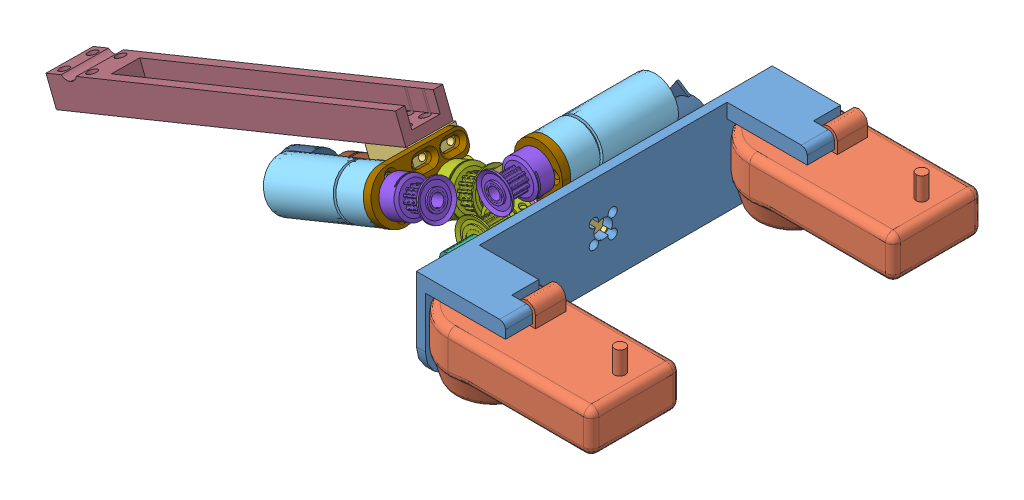
SolidWorks assembly VISION_HEAD_ASM, configuration Default. Lengths in mm.
Overall size (241.71 75.27 131.7).
29 component instances, 14 part files, 15 mates.
Components (placement in the parent):
- Head-Camera-Support-V2-1: Head-Camera-Support-V2 [Default] at origin size (30 32 119.8)
- LOGITECH_USB_CAM-1: LOGITECH_USB_CAM [Default] at (-11.43 -3.81 7.9) x (0 0 -1) z (0 -1 0) size (30.1 63.31 29.21)
- LOGITECH_USB_CAM-2: LOGITECH_USB_CAM [Default] at (-11.43 -3.81 -93.7) x (0 0 -1) z (0 -1 0) size (30.1 63.31 29.21)
- head-pin-joint-2: head-pin-joint [Default] at (-28 -14 -42.9) x (0 1 0) z (0 0 1) size (48.11 26.33 83.16)
  - n05-headyoke-1: n05-headyoke [Default] at origin size (15.88 21.91 15.88)
  - p1875bearing-57155K319-MCM-1: p1875bearing-57155K319-MCM [Default] at (0 13.97 5.5499) x (0 0 -1) z (0 -1 0) size (3.17 11.18 11.18)
  - p1875bearing-57155K319-MCM-2: p1875bearing-57155K319-MCM [Default] at (0 13.97 -5.5499) x (0 0 1) z (0 -1 0) size (3.17 11.18 11.18)
  - MAXON-AMAX16-110049-110323-1: MAXON-AMAX16-110049-110323 [Default] at (17.4625 8.128 -28.5125) x (0 0 -1) z (1 0 0) size (48.2 16 16)
  - n06-p1875shaft-1: n06-p1875shaft [Default] at (0 13.97 -15.0749) size (4.76 4.76 50.8)
  - a_6d16-016df2506-p1875bore-16teeth-1: a_6d16-016df2506-p1875bore-16teeth [Default] at (0 13.97 17.218) x (0.167713 -0.985836 0) z (0 0 -1) size (14.73 14.73 14.29)
  - a_6d16m012df6003-3mm-bored-to-4mm-1: a_6d16m012df6003-3mm-bored-to-4mm [Default] at (17.4625 8.128 17.2524) x (-0.948708 0.316155 0) z (0 0 -1) size (12.2 12.2 14.3)
  - a_6n16-015df1206-2: a_6n16-015df1206 [Default] at (-14.2838 6.954 15.9813) x (0.986257 0.164531 -0.015045) z (-0.021924 0.040076 -0.998956) size (14.1 14.1 11.13) (hidden)
  - n09-motor-holder-1: n09-motor-holder [Default] at (17.4625 8.128 7.9375) size (33.53 16.26 2.9)
  - POT-eti-sys-EUP125-1: POT-eti-sys-EUP125 [Default] at (0 13.97 -47.4345) x (0 0 -1) z (0.836462 -0.548026 0) size (30.58 15.39 13)
  - 000_helical-coupling-6208K53-MCM-1: 000_helical-coupling-6208K53-MCM [Default] at (0 13.97 -18.3769) size (12.7 12.7 19.05)
- head-pin-joint-3: head-pin-joint [Default] at (-90.0766 -18.4589 -43.0141) x (-0.003074 0.007569 0.999967) z (0.926512 0.376265 0) size (48.11 26.33 83.16)
  - n05-headyoke-1: n05-headyoke [Default] at origin size (15.88 21.91 15.88)
  - p1875bearing-57155K319-MCM-1: p1875bearing-57155K319-MCM [Default] at (0 13.97 5.5499) x (0 0 -1) z (0 -1 0) size (3.17 11.18 11.18)
  - p1875bearing-57155K319-MCM-2: p1875bearing-57155K319-MCM [Default] at (0 13.97 -5.5499) x (0 0 1) z (0 -1 0) size (3.17 11.18 11.18)
  - MAXON-AMAX16-110049-110323-1: MAXON-AMAX16-110049-110323 [Default] at (17.4625 8.128 -28.5125) x (0 0 -1) z (1 0 0) size (48.2 16 16)
  - n06-p1875shaft-1: n06-p1875shaft [Default] at (0 13.97 -15.0749) size (4.76 4.76 50.8)
  - a_6d16-016df2506-p1875bore-16teeth-1: a_6d16-016df2506-p1875bore-16teeth [Default] at (0 13.97 17.218) x (0.167713 -0.985836 0) z (0 0 -1) size (14.73 14.73 14.29)
  - a_6d16m012df6003-3mm-bored-to-4mm-1: a_6d16m012df6003-3mm-bored-to-4mm [Default] at (17.4625 8.128 17.2524) x (-0.948708 0.316155 0) z (0 0 -1) size (12.2 12.2 14.3)
  - a_6n16-015df1206-2: a_6n16-015df1206 [Default] at (-14.2838 6.954 15.9813) x (0.986257 0.164531 -0.015045) z (-0.021924 0.040076 -0.998956) size (14.1 14.1 11.13) (hidden)
  - n09-motor-holder-1: n09-motor-holder [Default] at (17.4625 8.128 7.9375) size (33.53 16.26 2.9)
  - POT-eti-sys-EUP125-1: POT-eti-sys-EUP125 [Default] at (0 13.97 -47.4345) x (0 0 -1) z (0.836462 -0.548026 0) size (30.58 15.39 13)
  - 000_helical-coupling-6208K53-MCM-1: 000_helical-coupling-6208K53-MCM [Default] at (0 13.97 -18.3769) size (12.7 12.7 19.05)
- n07-shaft-to-cams-1: n07-shaft-to-cams [Default] at (-41.97 -14 -38.1375) x (0.376265 -0.926512 0) z (0 0 -1) size (12.7 25.35 9.53)
- n08-neck-bar-1: n08-neck-bar [Default] at (-146.0222 -30.8988 -43.0919) x (-0.003074 0.007569 0.999967) z (0.926512 0.376265 0) size (15.88 9.53 127)
Mates (geometry in assembly coordinates):
- Concentric1: concentric aligned: cylinder of Head-Camera-Support-V2-1; cylinder of LOGITECH_USB_CAM-2
- Concentric2: concentric anti-aligned: cylinder of Head-Camera-Support-V2-1; cylinder of LOGITECH_USB_CAM-1
- Coincident1: coincident anti-aligned: plane of Head-Camera-Support-V2-1 through (0 0 7.9) normal (0 0 -1); plane of LOGITECH_USB_CAM-1 through (0 0 7.9) normal (0 0 1)
- Coincident2: coincident anti-aligned: plane of Head-Camera-Support-V2-1 through (0 0 -93.7) normal (0 0 -1); plane of LOGITECH_USB_CAM-2 through (0 0 -93.7) normal (0 0 1)
- Parallel1: parallel aligned: plane of Head-Camera-Support-V2-1 through (0 2 17) normal (0 1 0); plane of LOGITECH_USB_CAM-1 through (-11.43 -3.81 7.9) normal (0 1 0)
- Coincident4: coincident aligned: plane of LOGITECH_USB_CAM-1 through (-11.43 -3.81 7.9) normal (0 1 0); plane of LOGITECH_USB_CAM-2 through (-11.43 -3.81 -93.7) normal (0 1 0)
- Concentric5: concentric anti-aligned: cylinder of head-pin-joint-2/n06-p1875shaft-1; cylinder of n07-shaft-to-cams-1
- Distance1: distance = 0.3175 mm anti-aligned: plane of head-pin-joint-2/n05-headyoke-1 through (-32.064 -21.9375 -37.82) normal (0 0 -1); plane of n07-shaft-to-cams-1 through (-41.97 -14 -38.1375) normal (0 0 1)
- Concentric7: concentric aligned: cylinder of Head-Camera-Support-V2-1; cylinder of head-pin-joint-2/n05-headyoke-1
- Coincident7: coincident anti-aligned: plane of Head-Camera-Support-V2-1 through (-28 -30 -102.8) normal (-1 0 0); plane of head-pin-joint-2/n05-headyoke-1 through (-28 -6.0625 -34.9625) normal (1 0 0)
- Concentric8: concentric aligned: cylinder of Head-Camera-Support-V2-1; cylinder of head-pin-joint-2/n05-headyoke-1
- Concentric9: concentric aligned: cylinder of head-pin-joint-3/n06-p1875shaft-1; cylinder of n07-shaft-to-cams-1
- Coincident8: coincident anti-aligned: plane of head-pin-joint-3/n05-headyoke-1 through (-82.7468 -15.4123 -35.0769) normal (-0.376252 0.926481 -0.008169); plane of n08-neck-bar-1 through (-83.5805 -15.8908 -50.9514) normal (0.376252 -0.926481 0.008169)
- Concentric10: concentric anti-aligned: cylinder of head-pin-joint-3/n05-headyoke-1; cylinder of n08-neck-bar-1
- Concentric11: concentric anti-aligned: cylinder of head-pin-joint-3/n05-headyoke-1; cylinder of n08-neck-bar-1
